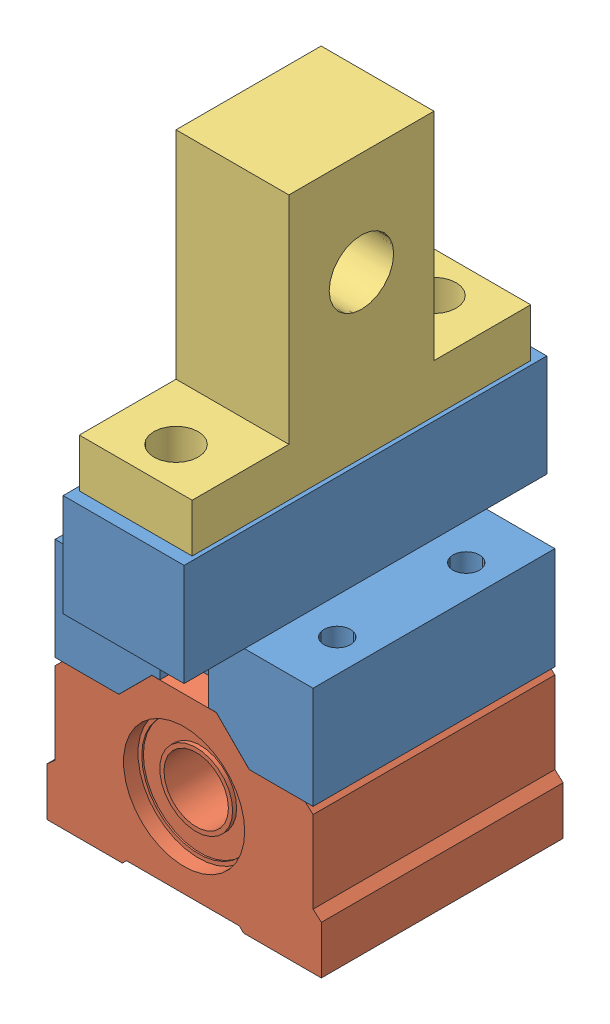
SolidWorks assembly Shaft Bearing, configuration Default. Lengths in mm.
Overall size (34.06 76.12 45).
3 component instances, 3 part files, 6 mates.
Components (placement in the parent):
- Shaft Support to Linear Bearing-1: Shaft Support to Linear Bearing [Default] at (13.9531 20.2649 38.2288) size (32 25.4 45)
- Linear Ball Bearing-1: Linear Ball Bearing [Défaut] at (13.9531 13.3207 53.2288) size (34.06 22 30)
- Linear Rod Support-1: Linear Rod Support [Default] at (6.9531 45.6649 38.2288) x (0 0 -1) z (1 0 0) size (42 32.8 14)
Mates (geometry in assembly coordinates):
- Concentric1: concentric anti-aligned: cylinder of Shaft Support to Linear Bearing 3D-1 through (13.9531 45.6649 54.2288) axis (0 -1 0) radius 2.75; cylinder of Linear Rod Support-1 through (13.9531 37.8868 54.2288) axis (0 1 0) radius 2.75
- Concentric2: concentric anti-aligned: cylinder of Shaft Support to Linear Bearing 3D-1 through (13.9531 45.6649 22.2288) axis (0 -1 0) radius 2.75; cylinder of Linear Rod Support-1 through (13.9531 37.8868 22.2288) axis (0 1 0) radius 2.75
- Concentric3: concentric anti-aligned: cylinder of Shaft Support to Linear Bearing 3D-1 through (25.9531 15.598 46.2288) axis (0 1 0) radius 1.65; cylinder of Linear Ball Bearing-1 through (25.9531 24.1469 46.2288) axis (0 -1 0) radius 1.65
- Concentric4: concentric anti-aligned: cylinder of Shaft Support to Linear Bearing 3D-1 through (1.9531 15.598 46.2288) axis (0 1 0) radius 1.65; cylinder of Linear Ball Bearing-1 through (1.9531 24.1469 46.2288) axis (0 -1 0) radius 1.65
- Coincident1: coincident anti-aligned: plane of Shaft Support to Linear Bearing 3D-1 through (5.8519 20.2649 53.2288) normal (0 -1 0); plane of Linear Ball Bearing-1 through (13.9531 20.2649 23.2288) normal (0 1 0)
- Coincident2: coincident anti-aligned: plane of Shaft Support to Linear Bearing 3D-1 through (13.9531 45.6649 38.2288) normal (0 1 0); plane of Linear Rod Support-1 through (20.9531 45.6649 59.2288) normal (0 -1 0)
